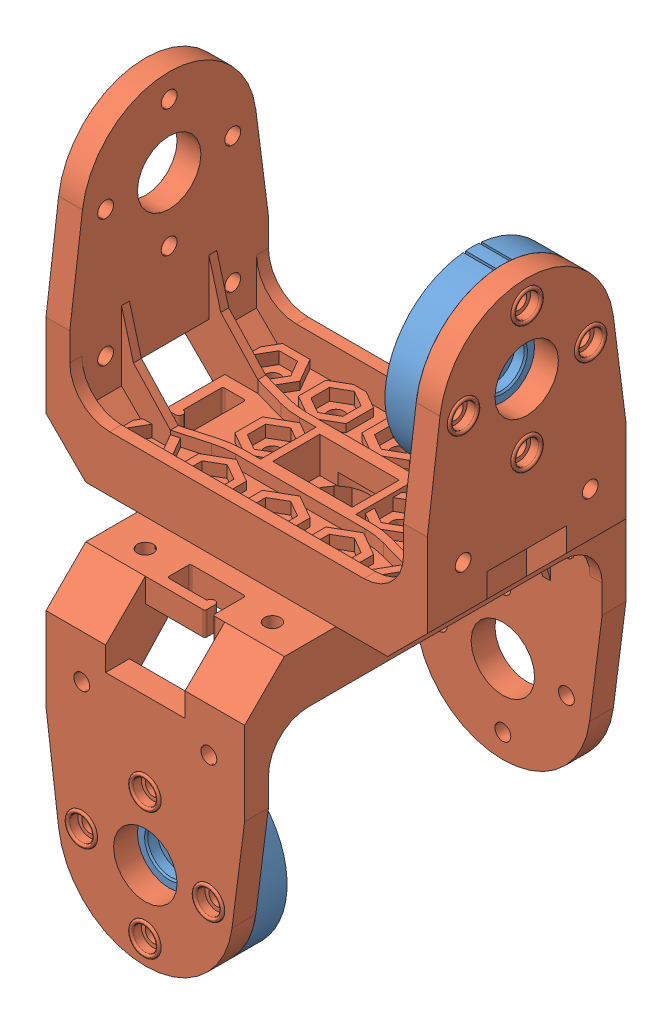
SolidWorks assembly Coxa_left, configuration Default. Lengths in mm.
Overall size (48.5 75 48.5).
4 component instances, 2 part files, 13 mates.
Components (placement in the parent):
- ServoHorn-2: ServoHorn [Default] at (0 0 -14.17) size (22 22 6.71)
- F2-1: F2 [Default] at (0 0 -14.3) x (1 0 0) z (0 0 -1) size (25 37.5 48.5)
- ServoHorn-1: ServoHorn [Default] at (0.1297 53 -14.2997) x (0 0 1) z (1 0 0) size (22 22 6.71)
- F2-2: F2 [Default] at (-0.0003 53 -14.2997) x (0 0 1) z (-1 0 0) size (25 37.5 48.5)
Mates (geometry in assembly coordinates):
- Concentric4: concentric anti-aligned: cylinder of F2-1 through (7.9997 16.5 -6.3) axis (0 1 0) radius 1; cylinder of F2-2 through (7.9997 36.5 -6.3) axis (0 -1 0) radius 1
- Concentric5: concentric anti-aligned: cylinder of F2-1 through (-8.0003 16.5 -6.3) axis (0 1 0) radius 1; cylinder of F2-2 through (-8.0003 36.5 -6.3) axis (0 -1 0) radius 1
- Coincident5: coincident anti-aligned: plane of F2-1 through (-12.5 26.5 -38.3) normal (0 1 0); plane of F2-2 through (-24.0003 26.5 -26.7997) normal (0 -1 0)
- Concentric6: concentric aligned: cylinder of F2-2 through (-24.0003 45 -14.2997) axis (1 0 0) radius 1; cylinder of ServoHorn-1 through (19.1597 45 -14.2997) axis (1 0 0) radius 1.05
- Concentric7: concentric aligned: cylinder of F2-2 through (-24.0003 53 -22.2997) axis (1 0 0) radius 1; cylinder of ServoHorn-1 through (19.1597 53 -22.2997) axis (1 0 0) radius 1.05
- Coincident6: coincident anti-aligned: plane of F2-2 through (20.9997 64.1221 -31.7861) normal (-1 0 0); plane of ServoHorn-1 through (20.9997 41.5628 -25.7425) normal (1 0 0)
- Concentric9: concentric aligned: cylinder of F2-1 through (8 0 -38.3) axis (0 0 1) radius 1; cylinder of ServoHorn-2 through (8 0 4.86) axis (0 0 1) radius 1.05
- Concentric10: concentric aligned: cylinder of F2-1 through (-8 0 -38.3) axis (0 0 1) radius 1; cylinder of ServoHorn-2 through (-8 0 4.86) axis (0 0 1) radius 1.05
- Coincident7: coincident anti-aligned: plane of F2-1 through (-17.4864 -11.1221 6.7) normal (0 0 -1); plane of ServoHorn-2 through (-11.4428 11.4372 6.7) normal (0 0 1)
- Concentric11: concentric: cylinder of ServoHorn-2 through (0 0 3.66) axis (0 0 -1) radius 2.95; point of assembly
- Coincident9: coincident: plane of ServoHorn-2 through (-4.1735 -4.1691 0) normal (0 0 -1); point of assembly
- Parallel1: parallel aligned: plane of ServoHorn-2 through (0 0 -14.17) normal (0 0 1); plane of assembly through (0 0 0) normal (0 0 1)
- Coincident11: coincident aligned: plane of ServoHorn-2 through (0 0 -14.17) normal (0 1 0); plane of assembly through (0 0 0) normal (0 1 0)
